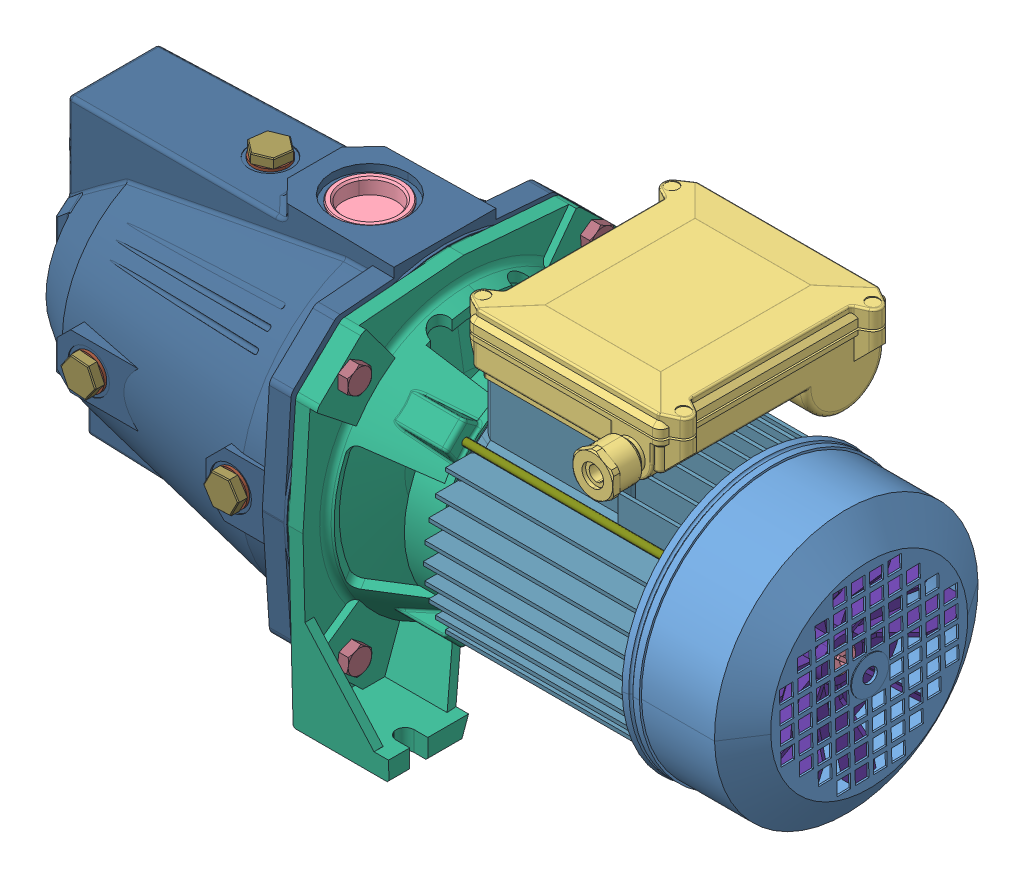
SolidWorks assembly AC1  CSwaterpumps.STEP, configuration Default. Lengths in mm.
Overall size (422.89 227.05 226.11).
62 component instances, 29 part files, 0 mates.
Components (placement in the parent):
- SKF_W_6202_2RS1.STEP-1: SKF_W_6202_2RS1.STEP [Default] at (-7.4882 -51.712 187) x (1 0 0) z (0 -0.817225 0.576319) size (11 35 35)
  - SKF_W_6202_2RS1_12.STEP-1: SKF_W_6202_2RS1_12.STEP [Default] x (1 0 0) z (0 -0.707107 0.707107) size (5.95 5.95 5.95)
  - SKF_W_6202_2RS1_12.STEP-2: SKF_W_6202_2RS1_12.STEP [Default] x (1 0 0) z (0 -1 0) size (5.95 5.95 5.95)
  - SKF_W_6202_2RS1_12.STEP-3: SKF_W_6202_2RS1_12.STEP [Default] x (1 0 0) z (0 -0.707107 -0.707107) size (5.95 5.95 5.95)
  - SKF_W_6202_2RS1_12.STEP-4: SKF_W_6202_2RS1_12.STEP [Default] x (1 0 0) z (0 0 -1) size (5.95 5.95 5.95)
  - SKF_W_6202_2RS1_12.STEP-5: SKF_W_6202_2RS1_12.STEP [Default] x (1 0 0) z (0 0.707107 -0.707107) size (5.95 5.95 5.95)
  - SKF_W_6202_2RS1_12.STEP-6: SKF_W_6202_2RS1_12.STEP [Default] x (1 0 0) z (0 1 0) size (5.95 5.95 5.95)
  - SKF_W_6202_2RS1_12.STEP-7: SKF_W_6202_2RS1_12.STEP [Default] x (1 0 0) z (0 0.707107 0.707107) size (5.95 5.95 5.95)
  - SKF_W_6202_2RS1_12.STEP-8: SKF_W_6202_2RS1_12.STEP [Default] at origin size (5.95 5.95 5.95)
  - SKF_W_6202_2RS1_21.STEP-1: SKF_W_6202_2RS1_21.STEP [Default] at origin size (11 35 35)
  - SKF_W_6202_2RS1_23.STEP-1: SKF_W_6202_2RS1_23.STEP [Default] at origin size (11 31.4 31.4)
- Albero AC1-50.STEP-1: Albero AC1-50.STEP [Default] at (-72.4882 -51.712 187) x (1 0 0) z (0 0.673906 0.738817) size (242.69 57.74 57.74)
  - Albero.STEP-1: Albero.STEP [Default] at origin size (242.69 17 17)
  - Rotore_70.STEP-1: Rotore_70.STEP [Default] at (138 0 0) x (1 0 0) z (0 0.997992 -0.063333) size (78 54.4 54.4)
- SKF_W_6202_2RS1.STEP-2: SKF_W_6202_2RS1.STEP [Default] at (131.5118 -51.712 187) x (1 0 0) z (0 0.000807 1) size (11 35 35)
  - SKF_W_6202_2RS1_12.STEP-1: SKF_W_6202_2RS1_12.STEP [Default] x (1 0 0) z (0 -0.707107 0.707107) size (5.95 5.95 5.95)
  - SKF_W_6202_2RS1_12.STEP-2: SKF_W_6202_2RS1_12.STEP [Default] x (1 0 0) z (0 -1 0) size (5.95 5.95 5.95)
  - SKF_W_6202_2RS1_12.STEP-3: SKF_W_6202_2RS1_12.STEP [Default] x (1 0 0) z (0 -0.707107 -0.707107) size (5.95 5.95 5.95)
  - SKF_W_6202_2RS1_12.STEP-4: SKF_W_6202_2RS1_12.STEP [Default] x (1 0 0) z (0 0 -1) size (5.95 5.95 5.95)
  - SKF_W_6202_2RS1_12.STEP-5: SKF_W_6202_2RS1_12.STEP [Default] x (1 0 0) z (0 0.707107 -0.707107) size (5.95 5.95 5.95)
  - SKF_W_6202_2RS1_12.STEP-6: SKF_W_6202_2RS1_12.STEP [Default] x (1 0 0) z (0 1 0) size (5.95 5.95 5.95)
  - SKF_W_6202_2RS1_12.STEP-7: SKF_W_6202_2RS1_12.STEP [Default] x (1 0 0) z (0 0.707107 0.707107) size (5.95 5.95 5.95)
  - SKF_W_6202_2RS1_12.STEP-8: SKF_W_6202_2RS1_12.STEP [Default] at origin size (5.95 5.95 5.95)
  - SKF_W_6202_2RS1_21.STEP-1: SKF_W_6202_2RS1_21.STEP [Default] at origin size (11 35 35)
  - SKF_W_6202_2RS1_23.STEP-1: SKF_W_6202_2RS1_23.STEP [Default] at origin size (11 31.4 31.4)
- CSWSM15_LAVORATO.STEP-1: CSWSM15_LAVORATO.STEP [Default] at (-47.9882 -51.712 187) x (0 0 1) z (0 1 0) size (178 63 187)
- girante.STEP-1: girante.STEP [Default] at (-53.4882 -347.4364 332.1727) x (0 -0.871898 0.489688) z (-1 0 0) size (130 130 35)
- tubo venturi.STEP-1: tubo venturi.STEP [Default] at (-119.9882 -25.8451 393.2914) x (0 -0.186214 -0.982509) z (1 0 0) size (37 37 114)
- ugello.STEP-1: ugello.STEP [Default] at (-69.9882 -64.9388 394.4857) x (0 0.001093 -0.999999) z (1 0 0) size (29.5 29.5 32.5)
- CSWCP15_02_LAVORATO.STEP-1: CSWCP15_02_LAVORATO.STEP [Default] at (-50.4882 -51.712 187) x (0 0 -1) z (0 1 0) size (178 187.5 188.6)
- rondella 1_4.STEP-1: rondella 1_4.STEP [Default] at (-81.9882 -51.712 273) x (0.853756 0.520673 0) z (0 0 1) size (19 19 1.5)
- rondella 1_4.STEP-2: rondella 1_4.STEP [Default] at (-176.9882 -51.712 257) x (0.999046 -0.043664 0) z (0 0 1) size (19 19 1.5)
- rondella 1_4.STEP-3: rondella 1_4.STEP [Default] at (-227.9882 -119.712 187) x (0 -0.39505 -0.91866) z (1 0 0) size (19 19 1.5)
- rondella 1_4.STEP-4: rondella 1_4.STEP [Default] at (-146.9882 30.288 187) x (-0.993292 0 -0.115636) z (0 1 0) size (19 19 1.5)
- tappo 1_4.STEP-1: tappo 1_4.STEP [Default] at (-81.9882 -51.712 274.5) x (-0.024072 0.99971 0) z (0 0 1) size (17.21 19.63 12)
- tappo 1_4.STEP-2: tappo 1_4.STEP [Default] at (-176.9882 -51.712 258.5) x (0.915726 0.401804 0) z (0 0 1) size (17.21 19.63 12)
- tappo 1_4.STEP-3: tappo 1_4.STEP [Default] at (-227.9882 -119.712 187) x (0 0.995154 0.098325) z (-1 0 0) size (17.21 19.63 12)
- tappo 1_4.STEP-4: tappo 1_4.STEP [Default] at (-146.9882 31.788 187) x (0.98774 0 0.156109) z (0 1 0) size (17.21 19.63 12)
- hex screw gradec_din_DIN EN 24018 - M8 x 25-NN.STEP-1: hex screw gradec_din_DIN EN 24018 - M8 x 25-NN.STEP [Default] at (-30.3132 15.4631 119.8249) x (-1 0 0) z (0 0.905975 -0.423332) size (30.68 15.01 13)
- hex screw gradec_din_DIN EN 24018 - M8 x 25-NN.STEP-2: hex screw gradec_din_DIN EN 24018 - M8 x 25-NN.STEP [Default] at (-30.3132 15.4631 254.1751) x (-1 0 0) z (0 -0.857106 0.515139) size (30.68 15.01 13)
- hex screw gradec_din_DIN EN 24018 - M8 x 25-NN.STEP-3: hex screw gradec_din_DIN EN 24018 - M8 x 25-NN.STEP [Default] at (-30.3132 -118.8872 254.1751) x (-1 0 0) z (0 0.924225 0.381849) size (30.68 15.01 13)
- hex screw gradec_din_DIN EN 24018 - M8 x 25-NN.STEP-4: hex screw gradec_din_DIN EN 24018 - M8 x 25-NN.STEP [Default] at (-30.3132 -118.8872 119.8249) x (-1 0 0) z (0 0.924225 0.381849) size (30.68 15.01 13)
- CARCASSA  MEC 71 B5.STEP-1: CARCASSA  MEC 71 B5.STEP [Default] at (6.0118 -51.712 187) size (123.1 146.01 140.01)
- Statore 110x55H70.STEP-1: Statore 110x55H70.STEP [Default] at (65.5118 -51.712 187) x (0 -0.042527 -0.999095) z (1 0 0) size (110 110 70)
- tirante  5_135.STEP-1: tirante  5_135.STEP [Default] at (129.3435 -7.5178 142.8058) x (-1 0 0) z (0 -0.966976 0.254869) size (137.4 8.08 7)
- tirante  5_135.STEP-2: tirante  5_135.STEP [Default] at (129.3435 -7.5178 231.1942) x (-1 0 0) z (0 -0.247652 0.968849) size (137.4 8.08 7)
- tirante  5_135.STEP-3: tirante  5_135.STEP [Default] at (129.3435 -95.9062 231.1942) x (-1 0 0) z (0 0.408772 0.912637) size (137.4 8.08 7)
- tirante  5_135.STEP-4: tirante  5_135.STEP [Default] at (129.3435 -95.9062 142.8058) x (-1 0 0) z (0 0.997691 -0.067921) size (137.4 8.08 7)
- Ventola MEC71  FORO 15.STEP-1: Ventola MEC71  FORO 15.STEP [Default] at (-55.3882 -51.712 187) x (0 0.785661 0.618657) z (1 0 0) size (141.97 141.97 22)
- CALOTTA MEC 71 CON TAGLIO.STEP-1: CALOTTA MEC 71 CON TAGLIO.STEP [Default] at (-55.2882 -51.712 187) x (0 -0.00305 -0.999995) z (1 0 0) size (113.34 113.34 26.54)
- Copriventola MEC 71  con bordo.STEP-1: Copriventola MEC 71  con bordo.STEP [Default] at (-55.3421 -51.712 187) x (0 -0.023098 0.999733) z (1 0 0) size (149.32 149.32 62.5)
- Diffusore AC1.STEP-1: Diffusore AC1.STEP [Default] at (-53.6882 -51.712 187) x (0 -0.558014 -0.829832) z (1 0 0) size (161.52 165 35.9)
- COPRIMORS_MEC63-71_MONOFASE_M4.STEP-1: COPRIMORS_MEC63-71_MONOFASE_M4.STEP [Default] at (46.2618 26.288 187) x (-1 0 0) z (0 0 -1) size (121.11 50.5 148)
- Tappo salvafiletto 1 pollice.STEP-1: Tappo salvafiletto 1 pollice.STEP [Default] at (-91.9882 28.5659 187) x (0 1 0) z (-0.463085 0 0.886314) size (9.54 36.1 36.1)
- Tappo salvafiletto 1 pollice.STEP-2: Tappo salvafiletto 1 pollice.STEP [Default] at (-228.7661 3.288 187) x (-1 0 0) z (0 -0.081748 0.996653) size (9.54 36.1 36.1)
- ROMPIGOCCIA  AC1.STEP-1: ROMPIGOCCIA  AC1.STEP [Default] at (-20.4882 -51.712 187) x (0 0.971718 0.236146) z (1 0 0) size (35 35 3)
- o-rings series g_din_O-ring DIN 3771 - 165x3.55.STEP-1: o-rings series g_din_O-ring DIN 3771 - 165x3.55.STEP [Default] at (-50.6571 -51.712 187) x (0 0 1) z (-1 0 0) size (172.1 172.1 3.55)
- Supporto H26.2.STEP-1: Supporto H26.2.STEP [Default] at (101.0118 -147.912 187) x (0.997353 0 0.072715) z (0 1 0) size (10 10 26.2)
- o-rings series g_din_O-ring DIN 3771 - 23.6x2.65.STEP-1: o-rings series g_din_O-ring DIN 3771 - 23.6x2.65.STEP [Default] at (-207.0758 -51.712 187) x (0 0.818265 0.574841) z (-1 0 0) size (28.9 28.9 2.65)
- o-rings series g_din_O-ring DIN 3771 - 25x3.55.STEP-1: o-rings series g_din_O-ring DIN 3771 - 25x3.55.STEP [Default] at (-171.3256 -51.712 187) x (0 0 -1) z (1 0 0) size (32.1 32.1 3.55)
- oring  venturi.STEP-1: oring  venturi.STEP [Default] at (-94.9882 -51.712 187) x (0 0 -1) z (1 0 0) size (37 37 3.1)
- tenuta meccanica___ _________.STEP-1: tenuta meccanica___ _________.STEP [Default] at (-47.7882 -51.3853 186.6215) x (-1 0 0) z (0 0 -1) size (18.3 27 27)
